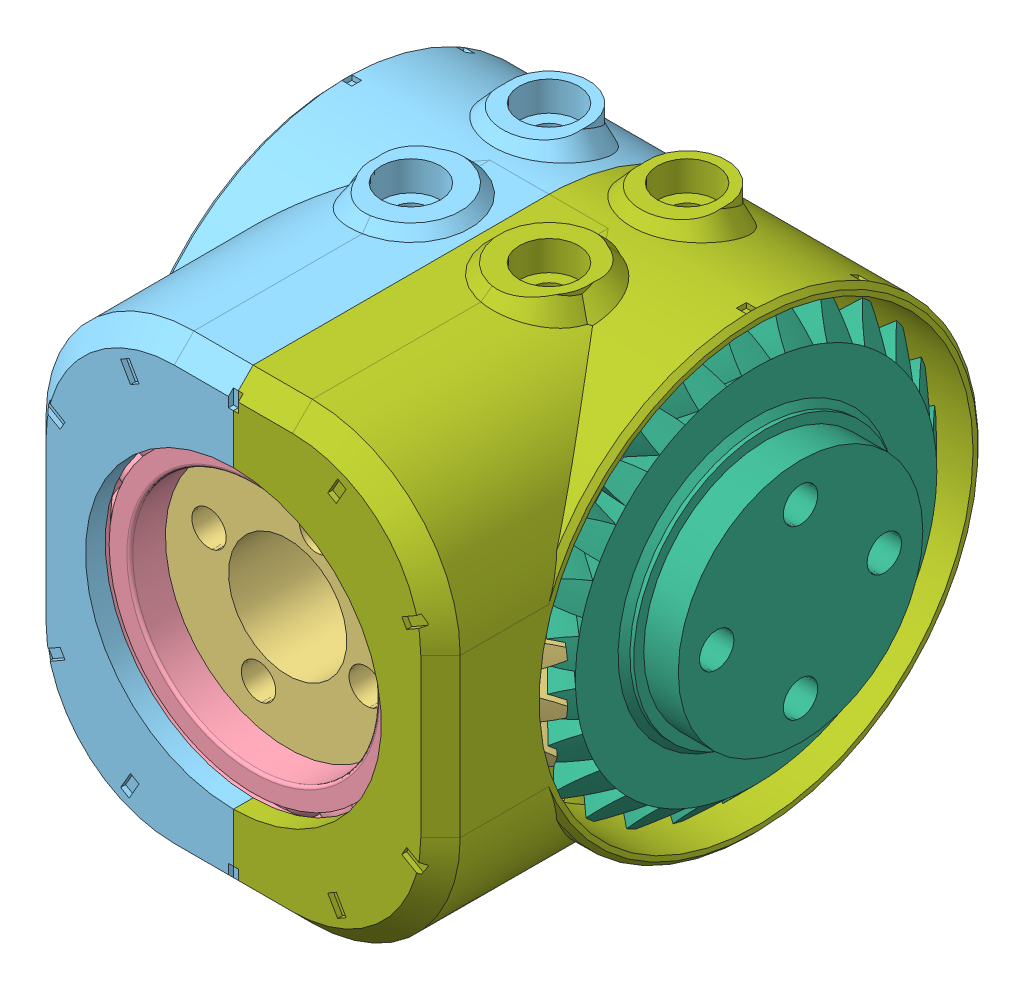
SolidWorks assembly Gelenk_4_V2, configuration Default. Lengths in mm.
Overall size (54.29 54.18 55).
9 component instances, 7 part files, 17 mates.
Components (placement in the parent):
- Gelenk_4_Frame_V2-1: Gelenk_4_Frame_V2 [Standard] at origin size (27.52 30.69 29)
- radial ball bearing_68_din-1: radial ball bearing_68_din [DIN 625 - 608 - 8,SI,NC,8_68] at (-10.5 0 0) x (-1 0 0) z (0 -0.924225 -0.381849) size (7 22 22)
- Differenzial_Getriebe_Zahnrad_1-2: Differenzial_Getriebe_Zahnrad_1 [Standard] at (0 0 1.7116) x (-0.937742 0.347333 0) z (0 0 -1) size (42.3 42.11 13.35)
- radial ball bearing_68_din-2: radial ball bearing_68_din [DIN 625 - 608 - 8,SI,NC,8_68] at (10.5 0 0) x (1 0 0) z (0 0.924225 0.381849) size (7 22 22)
- 6805_Radial_Bearring-1: 6805_Radial_Bearring [Standard] at (0 0 30) x (0.927702 -0.373322 0) z (-0.373322 -0.927702 0) size (37 7 37)
- Gelenk_4_Frame_2_links_V2-1: Gelenk_4_Frame_2_links_V2 [Standard] at origin size (21.58 48.06 55)
- Differenzial_Getriebe_Zahnrad_2-1: Differenzial_Getriebe_Zahnrad_2 [Standard] at (-0.7116 0 0) x (0 1 0) z (1 0 0) size (42.3 42.11 17.5)
- Differenzial_Getriebe_Zahnrad_2-2: Differenzial_Getriebe_Zahnrad_2 [Standard] at (0.7116 0 0) x (0 -1 0) z (-1 0 0) size (42.3 42.11 17.5)
- Gelenk_4_Frame_2_rechts_V2-1: Gelenk_4_Frame_2_rechts_V2 [Standard] at origin size (21.57 48.06 55)
Mates (geometry in assembly coordinates):
- Deckungsgleich1: coincident aligned: plane of Gelenk_4_Frame_V2-1 through (0 0 0) normal (0 0 1)
- Deckungsgleich2: coincident aligned: plane of Gelenk_4_Frame_V2-1 through (0 0 0) normal (0 1 0)
- Deckungsgleich3: coincident aligned: plane of Gelenk_4_Frame_V2-1 through (0 0 0) normal (1 0 0)
- Deckungsgleich4: coincident anti-aligned: plane of Gelenk_4_Frame_V2-1 through (-7 0 0) normal (-1 0 0); plane of radial ball bearing_68_din-1 through (-7 3.3985 -8.2256) normal (1 0 0)
- Konzentrisch1: concentric aligned: cylinder of Gelenk_4_Frame_V2-1 through (-7 0 0) axis (-1 0 0) radius 11.1; cylinder of radial ball bearing_68_din-1 through (10.1375 0 0) axis (-1 0 0) radius 11
- Konzentrisch3: concentric aligned: cylinder of Gelenk_4_Frame_V2-1 through (0 0 14) axis (0 0 -1) radius 13; cylinder of Differenzial_Getriebe_Zahnrad_1-2 through (0 0 0.7116) axis (0 0 -1) radius 12.4
- Konzentrisch5: concentric anti-aligned: cylinder of Differenzial_Getriebe_Zahnrad_1-2 through (0 0 0.7116) axis (0 0 -1) radius 12.4; cylinder of 6805_Radial_Bearring-1 through (0 0 25.5) axis (0 0 1) radius 18.5
- Deckungsgleich8: coincident anti-aligned: plane of Differenzial_Getriebe_Zahnrad_1-2 through (4.6543 12.5657 22) normal (0 0 1); plane of 6805_Radial_Bearring-1 through (-5.1145 -12.7095 22) normal (0 0 -1)
- Deckungsgleich9: coincident aligned: plane of Gelenk_4_Frame_2_links_V2-1 through (0 0 0) normal (1 0 0)
- Deckungsgleich10: coincident aligned: plane of Gelenk_4_Frame_2_links_V2-1 through (0 0 0) normal (0 1 0)
- Deckungsgleich11: coincident aligned: plane of Gelenk_4_Frame_2_links_V2-1 through (0 0 0) normal (0 0 1)
- Konzentrisch8: concentric aligned: cylinder of radial ball bearing_68_din-1 through (10.1375 0 0) axis (-1 0 0) radius 4; cylinder of Differenzial_Getriebe_Zahnrad_2-1 through (-8 0 0) axis (-1 0 0) radius 3.9
- Deckungsgleich15: coincident anti-aligned: plane of radial ball bearing_68_din-1 through (-14 1.642 -3.9742) normal (-1 0 0); plane of Differenzial_Getriebe_Zahnrad_2-1 through (-14 0 12) normal (1 0 0)
- Deckungsgleich16: coincident aligned: plane of Gelenk_4_Frame_2_rechts_V2-1 through (0 0 0) normal (0 0 1)
- Deckungsgleich17: coincident aligned: plane of Gelenk_4_Frame_2_rechts_V2-1 through (0 0 0) normal (0 1 0)
- Deckungsgleich18: coincident anti-aligned: plane of Gelenk_4_Frame_2_links_V2-1 through (0 30.0837 -23.0005) normal (1 0 0); plane of Gelenk_4_Frame_2_rechts_V2-1 through (0 30.0837 -23.0005) normal (-1 0 0)
- Deckungsgleich19: coincident anti-aligned: plane of 6805_Radial_Bearring-1 through (-6.4585 -16.0492 30) normal (0 0 1); plane of Gelenk_4_Frame_2_rechts_V2-1 through (0 0 30) normal (0 0 -1)
